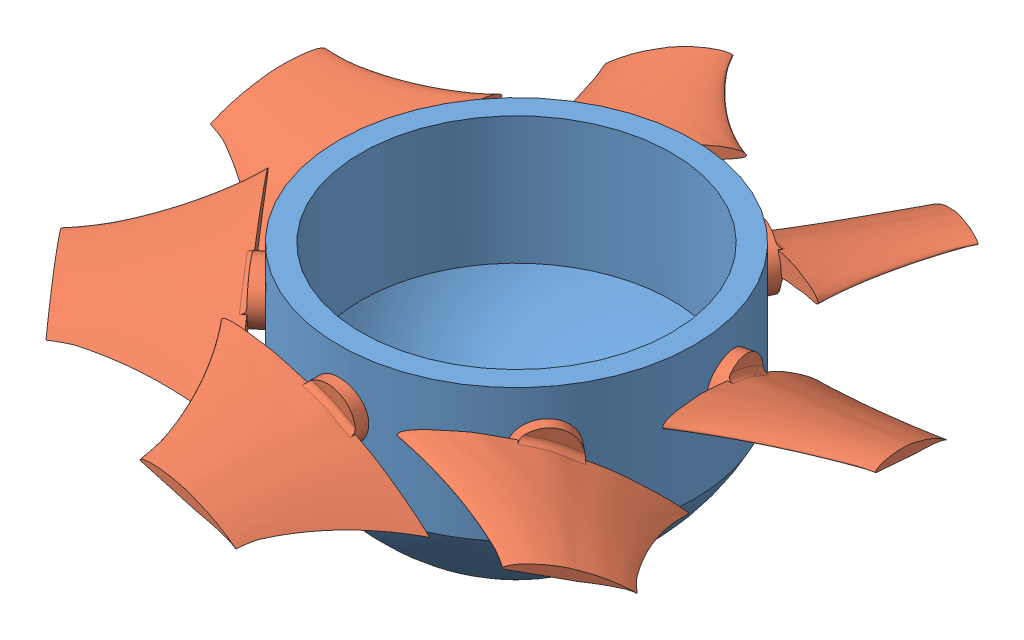
SolidWorks assembly Turbine, configuration Default. Lengths in mm.
Overall size (6242.45 2463.27 6095.25).
8 component instances, 2 part files, 6 mates.
Components (placement in the parent):
- Hub shaft-1: Hub shaft [Default] at (0 500 0) size (3200 2357.03 3200)
- Blade-8: Blade [Default] at (-942.0809 270.0906 1700) x (0.92543 -0.37892 0) z (0 0 1) size (2025.07 500 1399.93)
- Blade-9: Blade [Default] at (-1916.4914 270.0906 323.3841) x (0.576996 -0.37892 0.72353) z (-0.781831 0 0.62349) size (2025.07 500 1399.93)
- Blade-10: Blade [Default] at (-1447.7447 270.0906 -1296.7466) x (-0.205927 -0.37892 0.902227) z (-0.974928 0 -0.222521) size (2025.07 500 1399.93)
- Blade-11: Blade [Default] at (111.1832 270.0906 -1940.4007) x (-0.833783 -0.37892 0.401529) z (-0.433884 0 -0.900969) size (2025.07 500 1399.93)
- Blade-12: Blade [Default] at (1586.3879 270.0906 -1122.8935) x (-0.833783 -0.37892 -0.401529) z (0.433884 0 -0.900969) size (2025.07 500 1399.93)
- Blade-13: Blade [Default] at (1867.0102 270.0906 540.1754) x (-0.205927 -0.37892 -0.902227) z (0.974928 0 -0.222521) size (2025.07 500 1399.93)
- Blade-14: Blade [Default] at (741.7357 270.0906 1796.4812) x (0.576996 -0.37892 -0.72353) z (0.781831 0 0.62349) size (2025.07 500 1399.93)
Mates (geometry in assembly coordinates):
- Distance1: distance = 500 mm: plane of Hub shaft-1 through (1400 500 0) normal (0 1 0); line of Blade-8 through (0 0 1566.0727) axis (0 0 1)
- Coincident1: coincident aligned: plane of Hub shaft-1 through (0 500 0) normal (0 0 1); plane of assembly through (0 0 0) normal (0 0 1)
- Coincident2: coincident aligned: plane of Hub shaft-1 through (0 500 0) normal (1 0 0); plane of assembly through (0 0 0) normal (1 0 0)
- Coincident3: coincident aligned: line of Blade-8 through (0 0 1566.0727) axis (0 0 1); line of assembly
- Tangent1: tangent anti-aligned: cylinder of Hub shaft-1 through (0 -500 0) axis (0 -1 0) radius 1600; plane of Blade-8 through (0 0 1600) normal (0 0 -1)
- Concentric1: concentric aligned: cylinder of Hub shaft-1 through (0 -500 0) axis (0 -1 0) radius 1600; cylinder of Blade-8 through (0 -500 0) axis (0 -1 0) radius 1600
